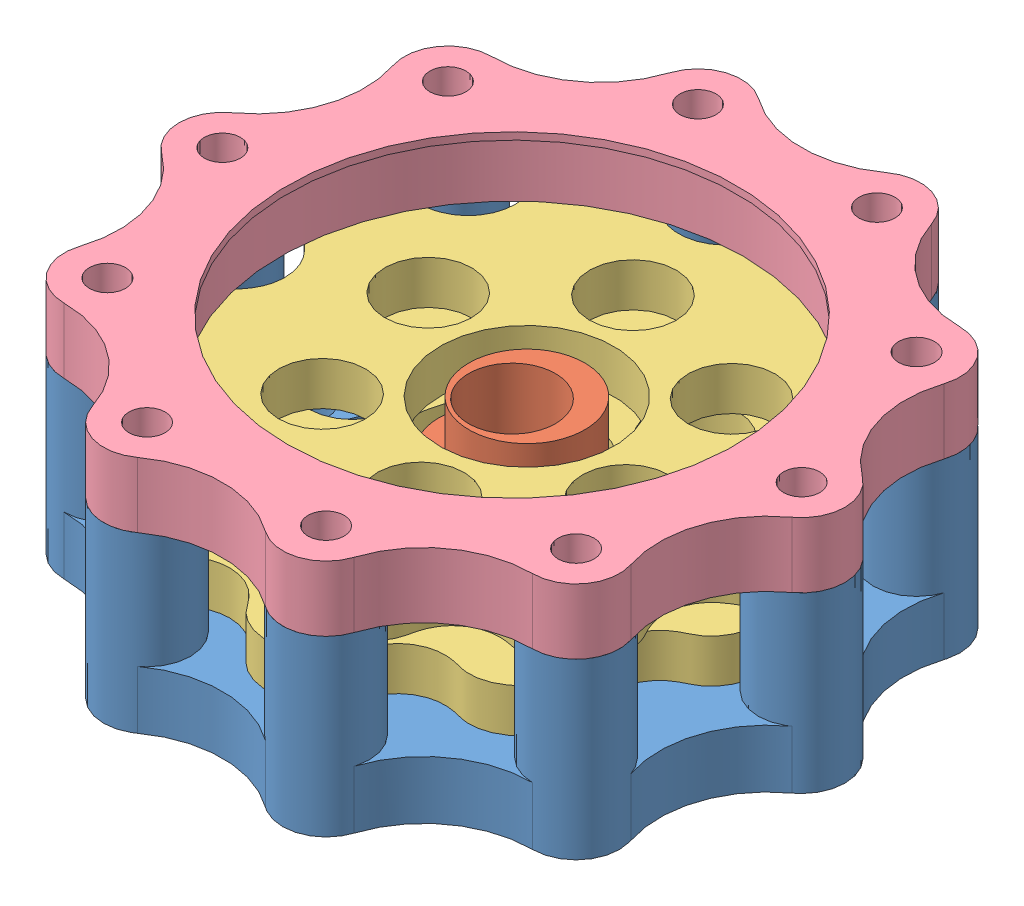
SolidWorks assembly 装配体1, configuration 默认. Lengths in mm.
Overall size (46 16.5 45.41).
5 component instances, 4 part files, 9 mates.
Components (placement in the parent):
- bottom-1: bottom [默认] at (-9.1411 -5.1459 46) size (46 12 44.04)
- input-1: input [默认] at (-9.1411 -0.6459 46) x (0.504695 0 -0.863298) z (0.863298 0 0.504695) size (9.5 7.5 8)
- cycloidal_disc-1: cycloidal_disc [默认] at (-9.5196 -0.6459 46.6475) size (36.17 3 36.61)
- cycloidal_disc-2: cycloidal_disc [默认] at (-8.7625 6.3541 45.3525) x (-0.960294 0 -0.27899) z (-0.27899 0 0.960294) size (36.17 3 36.61)
- top-1: top [默认] at (-9.1411 6.8541 46) size (46 4.5 44.04)
Mates (geometry in assembly coordinates):
- 重合1: coincident anti-aligned: plane of bottom-1 through (13.9169 -1.1459 41.7572) normal (0 1 0); plane of input-1 through (-9.1411 -1.1459 46) normal (0 -1 0)
- 同心2: concentric aligned: cylinder of input-1 through (-9.8838 2.3541 45.8956) axis (0 -1 0) radius 4; cylinder of cycloidal_disc-1 through (-9.8838 2.3541 45.8956) axis (0 -1 0) radius 6
- 重合2: coincident anti-aligned: plane of input-1 through (-9.8838 2.3541 45.8956) normal (0 -1 0); plane of cycloidal_disc-1 through (-8.9069 2.3541 27.9102) normal (0 1 0)
- 同心3: concentric anti-aligned: cylinder of input-1 through (-8.3984 3.3541 46.1044) axis (0 -1 0) radius 4; cylinder of cycloidal_disc-2 through (-8.3984 3.3541 46.1044) axis (0 1 0) radius 6
- 重合3: coincident anti-aligned: plane of input-1 through (-9.8838 3.3541 45.8956) normal (0 1 0); plane of cycloidal_disc-2 through (-4.3187 3.3541 28.5606) normal (0 -1 0)
- 同心4: concentric aligned: cylinder of bottom-1 through (-9.1411 -1.1459 46) axis (0 -1 0) radius 6; cylinder of input-1 through (-9.1411 2.3541 46) axis (0 -1 0) radius 3
- 同心5: concentric: cylinder of bottom-1 through (-29.1411 -1.1459 46) axis (0 -1 0) radius 3; cylinder of top-1 through (-29.1411 11.3541 46) axis (0 -1 0) radius 3
- 同心6: concentric: cylinder of bottom-1 through (-25.3214 -1.1459 57.7557) axis (0 -1 0) radius 3; cylinder of top-1 through (-25.3214 11.3541 57.7557) axis (0 -1 0) radius 3
- 重合4: coincident anti-aligned: plane of bottom-1 through (-25.3214 6.8541 57.7557) normal (0 1 0); plane of top-1 through (13.9169 6.8541 41.7572) normal (0 -1 0)
